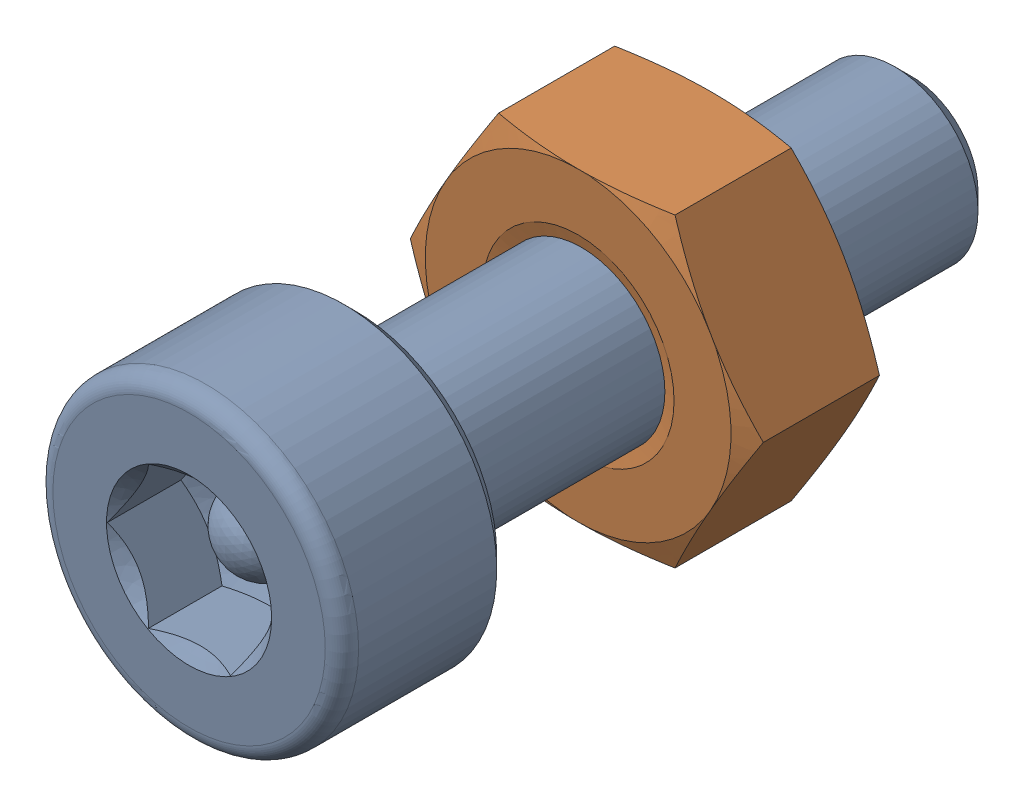
SolidWorks assembly Screw and Nut M3x010_014-1, configuration Varsayılan. Lengths in mm.
Overall size (6.35 5.5 13.14).
2 component instances, 2 part files, 0 mates.
Components (placement in the parent):
- M3x10-Screw013-1-1: M3x10-Screw013-1 [Varsayılan] at origin size (5.5 5.5 13.14)
- M3-Nut045-1-1: M3-Nut045-1 [Varsayılan] at (0 0 -4) x (-1 0 0) z (0 0 -1) size (6.35 5.5 2.4)
